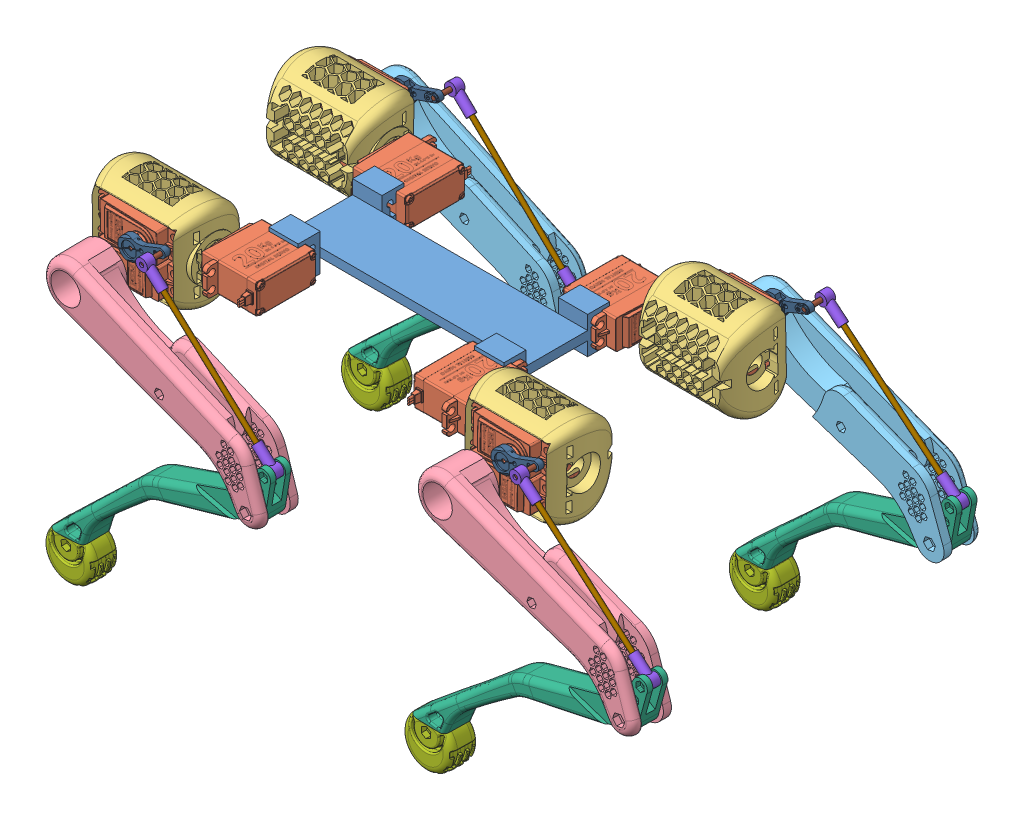
SolidWorks assembly ++Main_Assembly, configuration Default. Lengths in mm.
Overall size (432.52 222.98 243.72).
49 component instances, 11 part files, 112 mates.
Components (placement in the parent):
- Main_Body-1: Main_Body [Default] at (5.0922 136.3443 221.2659) size (160 25 72)
- DS3218MG_MS24_Digital_Servo_270-1: DS3218MG_MS24_Digital_Servo_270 [Default] at (145.0922 136.3151 160.5847) x (0 -1 0) z (0 0 1) size (20.1 45.99 55.6)
- DS3218MG_MS24_Digital_Servo_270-2: DS3218MG_MS24_Digital_Servo_270 [Default] at (145.0922 136.3151 281.9471) x (0 1 0) z (0 0 -1) size (20.1 45.99 55.6)
- DS3218MG_MS24_Digital_Servo_270-3: DS3218MG_MS24_Digital_Servo_270 [Default] at (-14.9078 136.3151 160.5847) x (0 1 0) z (0 0 1) size (20.1 45.99 55.6)
- DS3218MG_MS24_Digital_Servo_270-4: DS3218MG_MS24_Digital_Servo_270 [Default] at (-14.9078 136.3151 281.9471) x (0 -1 0) z (0 0 -1) size (20.1 45.99 55.6)
- HipJoint-1: HipJoint [Default] at (191.8422 136.3151 281.9471) x (1 0 0) z (0 0.020151 0.999797) size (67.23 58.77 49.18)
- HipJoint-2: HipJoint [Default] at (191.8422 136.3151 160.5847) x (1 0 0) z (0 0.018154 -0.999835) size (67.23 58.77 49.18)
- HipJoint-3: HipJoint [Default] at (-61.6578 136.3151 160.5847) x (-1 0 0) z (0 -0.032164 -0.999483) size (67.23 58.77 49.18)
- HipJoint-4: HipJoint [Default] at (-61.6578 136.3151 281.9471) x (-1 0 0) z (0 -0.01495 0.999888) size (67.23 58.77 49.18)
- DS3218MG_MS24_Digital_Servo_270-5: DS3218MG_MS24_Digital_Servo_270 [Default] at (-51.4078 147.1046 296.11) x (0 -0.999888 -0.01495) z (-1 0 0) size (20.1 45.99 55.6)
- DS3218MG_MS24_Digital_Servo_270-6: DS3218MG_MS24_Digital_Servo_270 [Default] at (-71.9078 125.107 295.7811) x (0 0.999888 0.01495) z (1 0 0) size (20.1 45.99 55.6)
- DS3218MG_MS24_Digital_Servo_270-7: DS3218MG_MS24_Digital_Servo_270 [Default] at (181.5922 125.5994 296.1659) x (0 0.999797 -0.020151) z (1 0 0) size (20.1 45.99 55.6)
- DS3218MG_MS24_Digital_Servo_270-8: DS3218MG_MS24_Digital_Servo_270 [Default] at (202.0922 147.6949 295.7206) x (0 -0.999797 0.020151) z (-1 0 0) size (20.1 45.99 55.6)
- DS3218MG_MS24_Digital_Servo_270-10: DS3218MG_MS24_Digital_Servo_270 [Default] at (201.5922 147.5674 146.7867) x (0 0.999835 0.018154) z (-1 0 0) size (20.1 45.99 55.6)
- DS3218MG_MS24_Digital_Servo_270-11: DS3218MG_MS24_Digital_Servo_270 [Default] at (182.0922 125.5711 146.3873) x (0 -0.999835 -0.018154) z (1 0 0) size (20.1 45.99 55.6)
- DS3218MG_MS24_Digital_Servo_270-12: DS3218MG_MS24_Digital_Servo_270 [Default] at (-71.4078 124.7705 146.949) x (0 -0.999483 0.032164) z (1 0 0) size (20.1 45.99 55.6)
- DS3218MG_MS24_Digital_Servo_270-13: DS3218MG_MS24_Digital_Servo_270 [Default] at (-51.9078 146.8591 146.2382) x (0 0.999483 -0.032164) z (-1 0 0) size (20.1 45.99 55.6)
- Left_Thigh-1: Left_Thigh [Default] at (238.4344 106.9954 326.3469) x (0 0.020151 0.999797) z (-0.94737 0.320075 -0.006451) size (26.29 49.21 165.28)
- Left_Thigh-2: Left_Thigh [Default] at (-16.0368 102.7909 325.2508) x (0 -0.01495 0.999888) z (-0.931184 0.36451 0.00545) size (26.29 49.21 165.28)
- Right_Thigh-1: Right_Thigh [Default] at (238.6676 105.2996 162.2219) x (0 -0.018154 0.999835) z (-0.942923 0.332955 0.006045) size (26.29 49.21 165.28)
- Right_Thigh-2: Right_Thigh [Default] at (-15.4072 103.7636 163.8334) x (0 0.032164 0.999483) z (-0.933343 0.358799 -0.011546) size (26.29 49.21 165.28)
- Leg_Universal-1: Leg_Universal [Default] at (-18.5337 16.056 324.454) x (0 -0.01495 0.999888) z (-0.987227 -0.159304 -0.002382) size (27.56 93.87 164.52)
- Leg_Universal-2: Leg_Universal [Default] at (-18.251 17.1977 120.0951) x (0 0.032164 0.999483) z (-0.989939 -0.14142 0.004551) size (27.56 93.87 164.52)
- Leg_Universal-3: Leg_Universal [Default] at (237.16 22.9219 114.2185) x (0 -0.018154 0.999835) z (-0.990021 -0.1409 -0.002558) size (27.56 93.87 164.52)
- Leg_Universal-4: Leg_Universal [Default] at (235.6218 28.8095 328.4229) x (0 0.020151 0.999797) z (-0.996606 -0.082305 0.001659) size (27.56 93.87 164.52)
- Feet-1: Feet [Default] at (-76.7895 -31.4649 323.4934) x (0 -0.01495 0.999888) z (-0.998583 -0.053205 -0.000796) size (21.73 29.66 33.85)
- Feet-2: Feet [Default] at (173.8572 -14.0583 329.0368) x (0 -0.020151 -0.999797) z (0.999703 -0.024346 0.000491) size (21.73 29.66 33.85)
- Feet-3: Feet [Default] at (178.5295 -23.4953 113.6258) x (0 -0.018154 0.999835) z (-0.999401 -0.034613 -0.000628) size (21.73 29.66 33.85)
- Feet-4: Feet [Default] at (-76.8547 -29.2243 121.8391) x (0 0.032164 0.999483) z (-0.99938 -0.035176 0.001132) size (21.73 29.66 33.85)
- Ball_Bearing_End_Joint-1: Ball_Bearing_End_Joint [Default] at (314.8505 81.1585 327.1177) x (0.639096 0.768971 -0.015498) z (0 -0.020151 -0.999797) size (8 20 6)
- Ball_Bearing_End_Joint-2: Ball_Bearing_End_Joint [Default] at (313.1644 79.8517 115.5023) x (0.650252 0.759593 0.013792) z (0 0.018154 -0.999835) size (8 20 6)
- Ball_Bearing_End_Joint-3: Ball_Bearing_End_Joint [Default] at (56.3978 74.4014 325.0763) x (0.685285 0.728193 0.010888) z (0 0.01495 -0.999888) size (8 20 6)
- Ball_Bearing_End_Joint-4: Ball_Bearing_End_Joint [Default] at (57.7206 74.1637 118.512) x (0.67212 0.74006 -0.023816) z (0 -0.032164 -0.999483) size (8 20 6)
- Long_Metal_Rod-1: Long_Metal_Rod [Default] at (13.4296 114.8287 325.6808) x (-0.138748 -0.132795 -0.981384) z (-0.728275 0.685209 0.010245) size (3 3 100)
- Long_Metal_Rod-2: Long_Metal_Rod [Default] at (14.0344 113.7983 117.2365) x (0.411304 0.478318 0.775913) z (-0.740443 0.671772 -0.021618) size (3 3 100)
- Long_Metal_Rod-3: Long_Metal_Rod [Default] at (269.472 118.8575 326.3579) x (0.046921 0.076552 0.995961) z (0.769127 -0.638967 0.012878) size (3 3 100)
- Long_Metal_Rod-4: Long_Metal_Rod [Default] at (268.341 118.2103 116.1987) x (-0.048668 -0.074954 0.995999) z (-0.759718 0.650145 0.011805) size (3 3 100)
- Servo_arm_25T-1: Servo_arm_25T [Default] at (-51.9078 146.219 126.3485) x (-0.94707 -0.320861 0.010325) z (-0.321027 0.94658 -0.030461) size (33.87 4.68 15)
- Servo_arm_25T-2: Servo_arm_25T [Default] at (201.5922 147.9287 126.89) x (-0.932997 -0.359824 -0.006533) z (-0.359884 0.932843 0.016938) size (33.87 4.68 15)
- Servo_arm_25T-3: Servo_arm_25T [Default] at (202.0922 148.0959 315.6166) x (-0.936228 -0.351321 0.007081) z (0.351392 -0.936038 0.018866) size (33.87 4.68 15)
- Servo_arm_25T-4: Servo_arm_25T [Default] at (-51.4078 146.807 316.0078) x (-0.930604 -0.365987 -0.005472) z (0.366028 -0.9305 -0.013913) size (33.87 4.68 15)
- Ball_Bearing_End_Joint-5: Ball_Bearing_End_Joint [Default] at (-29.5386 155.256 326.2852) x (0.685285 0.728193 0.010888) z (0 -0.01495 0.999888) size (8 20 6)
- Ball_Bearing_End_Joint-6: Ball_Bearing_End_Joint [Default] at (224.0935 156.5565 325.5981) x (-0.639096 -0.768971 0.015498) z (0 -0.020151 -0.999797) size (8 20 6)
- Ball_Bearing_End_Joint-7: Ball_Bearing_End_Joint [Default] at (223.5176 156.5688 116.8952) x (0.650252 0.759593 0.013792) z (0 -0.018154 0.999835) size (8 20 6)
- Ball_Bearing_End_Joint-8: Ball_Bearing_End_Joint [Default] at (-29.6517 153.4328 115.9611) x (-0.67212 -0.74006 0.023816) z (0 -0.032164 -0.999483) size (8 20 6)
- Short_Metal_Rod-1: Short_Metal_Rod [Default] at (-29.5386 155.3233 321.7857) x (0.999839 0.017951 0.000268) z (0 -0.01495 0.999888) size (3 3 16.55)
- Short_Metal_Rod-2: Short_Metal_Rod [Default] at (224.0935 156.4658 321.099) x (1 0 0) z (0 0.020151 0.999797) size (3 3 16.55)
- Short_Metal_Rod-3: Short_Metal_Rod [Default] at (223.5176 156.4191 125.1439) x (1 0.000002 0) z (0 -0.018154 0.999835) size (3 3 16.55)
- Short_Metal_Rod-4: Short_Metal_Rod [Default] at (-29.6517 153.6981 124.2068) x (0.999998 -0.001781 0.000057) z (0 0.032164 0.999483) size (3 3 16.55)
Mates (geometry in assembly coordinates):
- Coincident1: coincident anti-aligned: plane of Body-1 through (145.0922 136.3443 251.9471) normal (0 0 1); plane of DS3218MG MS24 Digital Servo 270-2 through (125.0922 126.3151 251.9471) normal (0 0 -1)
- Coincident2: coincident anti-aligned: plane of Body-1 through (145.0922 126.3151 221.2659) normal (0 1 0); plane of DS3218MG MS24 Digital Servo 270-2 through (156.0922 126.3151 290.9471) normal (0 -1 0)
- Coincident3: coincident anti-aligned: plane of Body-1 through (145.0922 136.3443 221.2659) normal (1 0 0); plane of DS3218MG MS24 Digital Servo 270-2 through (145.0922 145.3151 254.9471) normal (-1 0 0)
- Coincident4: coincident anti-aligned: plane of Body-1 through (145.0922 126.3151 221.2659) normal (0 1 0); plane of DS3218MG MS24 Digital Servo 270-1 through (156.0922 126.3151 189.5847) normal (0 -1 0)
- Coincident5: coincident anti-aligned: plane of Body-1 through (145.0922 136.3443 221.2659) normal (1 0 0); plane of DS3218MG MS24 Digital Servo 270-1 through (145.0922 127.3151 187.5847) normal (-1 0 0)
- Coincident6: coincident anti-aligned: plane of Body-1 through (145.0922 136.3443 190.5847) normal (0 0 -1); plane of DS3218MG MS24 Digital Servo 270-1 through (125.0922 146.3151 190.5847) normal (0 0 1)
- Coincident7: coincident anti-aligned: plane of Body-1 through (-14.9078 126.3151 221.2659) normal (0 1 0); plane of DS3218MG MS24 Digital Servo 270-3 through (-25.9078 126.3151 151.5847) normal (0 -1 0)
- Coincident8: coincident anti-aligned: plane of Body-1 through (-14.9078 136.3443 190.5847) normal (0 0 -1); plane of DS3218MG MS24 Digital Servo 270-3 through (5.0922 126.3151 190.5847) normal (0 0 1)
- Coincident9: coincident anti-aligned: plane of Body-1 through (-14.9078 136.3443 221.2659) normal (-1 0 0); plane of DS3218MG MS24 Digital Servo 270-3 through (-14.9078 145.3151 187.5847) normal (1 0 0)
- Coincident15: coincident anti-aligned: plane of Body-1 through (-14.9078 136.3443 251.9471) normal (0 0 1); plane of DS3218MG MS24 Digital Servo 270-4 through (5.0922 146.3151 251.9471) normal (0 0 -1)
- Coincident16: coincident anti-aligned: plane of Body-1 through (-14.9078 126.3151 221.2659) normal (0 1 0); plane of DS3218MG MS24 Digital Servo 270-4 through (5.0922 126.3151 291.9471) normal (0 -1 0)
- Coincident17: coincident anti-aligned: plane of Body-1 through (-14.9078 136.3443 221.2659) normal (-1 0 0); plane of DS3218MG MS24 Digital Servo 270-4 through (-14.9078 127.3151 254.9471) normal (1 0 0)
- Concentric1: concentric aligned: circle of DS3218MG MS24 Digital Servo 270-2; circle of HipJoint-1
- Distance2: distance = 0 mm anti-aligned: plane of DS3218MG MS24 Digital Servo 270-2 through (163.4922 136.3151 281.9471) normal (1 0 0); plane of HipJoint-1 through (163.4922 136.3151 281.9471) normal (-1 0 0)
- Concentric2: concentric aligned: circle of DS3218MG MS24 Digital Servo 270-1; circle of HipJoint-2
- Distance1: distance = 0 mm anti-aligned: plane of HipJoint-2 through (163.4922 136.3151 160.5847) normal (-1 0 0); plane of DS3218MG MS24 Digital Servo 270-1 through (163.4922 136.3151 160.5847) normal (1 0 0)
- Concentric3: concentric aligned: circle of DS3218MG MS24 Digital Servo 270-3; circle of HipJoint-3
- Distance3: distance = 0 mm anti-aligned: plane of HipJoint-3 through (-33.3078 136.3151 160.5847) normal (1 0 0); plane of DS3218MG MS24 Digital Servo 270-3 through (-33.3078 136.3151 160.5847) normal (-1 0 0)
- Concentric4: concentric aligned: circle of DS3218MG MS24 Digital Servo 270-4; circle of HipJoint-4
- Distance4: distance = 0 mm anti-aligned: plane of HipJoint-4 through (-33.3078 136.3151 281.9471) normal (1 0 0); plane of DS3218MG MS24 Digital Servo 270-4 through (-33.3078 136.3151 281.9471) normal (-1 0 0)
- Coincident23: coincident anti-aligned: plane of HipJoint-4 through (-81.9078 136.5244 267.9487) normal (1 0 0); plane of DS3218MG MS24 Digital Servo 270-6 through (-81.9078 115.4071 275.6338) normal (-1 0 0)
- Coincident24: coincident anti-aligned: plane of HipJoint-4 through (-61.6578 136.1058 295.9456) normal (0 -0.01495 0.999888); plane of DS3218MG MS24 Digital Servo 270-6 through (-44.9078 134.106 295.9157) normal (0 0.01495 -0.999888)
- Coincident25: coincident anti-aligned: plane of HipJoint-4 through (-61.6578 135.5245 267.9337) normal (0 -0.999888 -0.01495); plane of DS3218MG MS24 Digital Servo 270-6 through (-81.9078 135.4049 275.9328) normal (0 0.999888 0.01495)
- Coincident26: coincident anti-aligned: plane of HipJoint-4 through (-41.4078 136.5244 267.9487) normal (-1 0 0); plane of DS3218MG MS24 Digital Servo 270-5 through (-41.4078 157.4024 276.2617) normal (1 0 0)
- Coincident27: coincident anti-aligned: plane of HipJoint-4 through (-61.6578 136.1058 295.9456) normal (0 -0.01495 0.999888); plane of DS3218MG MS24 Digital Servo 270-5 through (-78.4078 138.1056 295.9755) normal (0 0.01495 -0.999888)
- Coincident28: coincident anti-aligned: plane of HipJoint-4 through (-61.6578 137.5243 267.9636) normal (0 0.999888 0.01495); plane of DS3218MG MS24 Digital Servo 270-5 through (-41.4078 137.4047 275.9627) normal (0 -0.999888 -0.01495)
- Coincident29: coincident anti-aligned: plane of HipJoint-1 through (212.0922 136.033 267.95) normal (-1 0 0); plane of DS3218MG MS24 Digital Servo 270-8 through (212.0922 157.2899 275.5232) normal (1 0 0)
- Coincident30: coincident anti-aligned: plane of HipJoint-1 through (191.8422 157.1287 267.5248) normal (0 -0.999797 0.020151); plane of DS3218MG MS24 Digital Servo 270-8 through (212.0922 157.2899 275.5232) normal (0 0.999797 -0.020151)
- Coincident31: coincident anti-aligned: plane of HipJoint-1 through (191.8422 136.5972 295.9443) normal (0 0.020151 0.999797); plane of DS3218MG MS24 Digital Servo 270-8 through (175.0922 138.6968 295.902) normal (0 -0.020151 -0.999797)
- Coincident32: coincident anti-aligned: plane of HipJoint-1 through (171.5922 136.033 267.95) normal (1 0 0); plane of DS3218MG MS24 Digital Servo 270-7 through (171.5922 115.1984 276.3715) normal (-1 0 0)
- Coincident33: coincident anti-aligned: plane of HipJoint-1 through (191.8422 135.0332 267.9701) normal (0 -0.999797 0.020151); plane of DS3218MG MS24 Digital Servo 270-7 through (171.5922 135.1944 275.9685) normal (0 0.999797 -0.020151)
- Coincident34: coincident anti-aligned: plane of HipJoint-1 through (191.8422 136.5972 295.9443) normal (0 0.020151 0.999797); plane of DS3218MG MS24 Digital Servo 270-7 through (208.5922 134.5976 295.9846) normal (0 -0.020151 -0.999797)
- Concentric6: concentric aligned: circle of DS3218MG MS24 Digital Servo 270-6; circle of Left Thigh-2
- Distance18: distance = 2 mm anti-aligned: plane of Left_Thigh-2 through (-71.9078 124.802 316.1788) normal (0 0.01495 -0.999888); plane of DS3218MG_MS24_Digital_Servo_270-6 through (-71.9078 124.8319 314.1791) normal (0 -0.01495 0.999888)
- Concentric7: concentric aligned: circle of DS3218MG MS24 Digital Servo 270-7; circle of Left Thigh-1
- Distance19: distance = 2 mm anti-aligned: plane of Left_Thigh-1 through (181.5922 126.0105 316.5618) normal (0 -0.020151 -0.999797); plane of DS3218MG_MS24_Digital_Servo_270-7 through (181.5922 125.9702 314.5622) normal (0 0.020151 0.999797)
- Coincident37: coincident anti-aligned: plane of HipJoint-2 through (212.0922 136.0609 174.5824) normal (-1 0 0); plane of DS3218MG MS24 Digital Servo 270-9 through (212.0922 135.2063 166.5656) normal (1 0 0)
- Coincident38: coincident anti-aligned: plane of HipJoint-2 through (191.8422 135.0611 174.5643) normal (0 -0.999835 -0.018154); plane of DS3218MG MS24 Digital Servo 270-9 through (172.0922 135.2063 166.5656) normal (0 0.999835 0.018154)
- Coincident39: coincident anti-aligned: plane of HipJoint-2 through (191.8422 136.5692 146.587) normal (0 0.018154 -0.999835); plane of DS3218MG MS24 Digital Servo 270-9 through (209.0922 116.5725 146.224) normal (0 -0.018154 0.999835)
- Coincident40: coincident anti-aligned: plane of HipJoint-2 through (171.5922 136.0609 174.5824) normal (1 0 0); plane of DS3218MG MS24 Digital Servo 270-10 through (171.5922 137.206 166.6019) normal (-1 0 0)
- Coincident41: coincident anti-aligned: plane of HipJoint-2 through (191.8422 137.0608 174.6006) normal (0 0.999835 0.018154); plane of DS3218MG MS24 Digital Servo 270-10 through (211.5922 137.206 166.6019) normal (0 -0.999835 -0.018154)
- Coincident42: coincident anti-aligned: plane of HipJoint-2 through (191.8422 136.5692 146.587) normal (0 0.018154 -0.999835); plane of DS3218MG MS24 Digital Servo 270-10 through (174.5922 156.5659 146.9501) normal (0 -0.018154 0.999835)
- Coincident43: coincident anti-aligned: plane of HipJoint-3 through (-41.4078 136.7654 174.5775) normal (-1 0 0); plane of DS3218MG MS24 Digital Servo 270-11 through (-41.4078 135.4086 166.617) normal (1 0 0)
- Coincident44: coincident anti-aligned: plane of HipJoint-3 through (-61.6578 135.8648 146.592) normal (0 -0.032164 -0.999483); plane of DS3218MG MS24 Digital Servo 270-11 through (-44.4078 115.7752 147.2385) normal (0 0.032164 0.999483)
- Coincident45: coincident anti-aligned: plane of HipJoint-3 through (-61.6578 115.6763 175.2561) normal (0 0.999483 -0.032164); plane of DS3218MG MS24 Digital Servo 270-11 through (-81.4078 115.419 167.2603) normal (0 -0.999483 0.032164)
- Coincident46: coincident anti-aligned: plane of HipJoint-3 through (-81.9078 136.7654 174.5775) normal (1 0 0); plane of DS3218MG MS24 Digital Servo 270-12 through (-81.9078 137.5075 166.5495) normal (-1 0 0)
- Coincident47: coincident anti-aligned: plane of HipJoint-3 through (-61.6578 137.7649 174.5453) normal (0 0.999483 -0.032164); plane of DS3218MG MS24 Digital Servo 270-12 through (-41.9078 137.5075 166.5495) normal (0 -0.999483 0.032164)
- Coincident48: coincident anti-aligned: plane of HipJoint-3 through (-61.6578 135.8648 146.592) normal (0 -0.032164 -0.999483); plane of DS3218MG MS24 Digital Servo 270-12 through (-78.9078 155.8544 145.9487) normal (0 0.032164 0.999483)
- Concentric8: concentric aligned: circle of DS3218MG MS24 Digital Servo 270-9; circle of Right Thigh-1
- Distance20: distance = 2 mm anti-aligned: plane of DS3218MG MS24 Digital Servo 270-9 through (182.0922 125.9051 127.9904) normal (0 0.018154 -0.999835); plane of Right Thigh-1 through (182.0922 125.9414 125.9907) normal (0 -0.018154 0.999835)
- Concentric9: concentric anti-aligned: circle of DS3218MG MS24 Digital Servo 270-11; circle of Right Thigh-2
- Distance21: distance = 2 mm anti-aligned: plane of DS3218MG MS24 Digital Servo 270-11 through (-71.4078 124.1787 128.5585) normal (0 -0.032164 -0.999483); plane of Right Thigh-2 through (-71.4078 124.1144 126.5596) normal (0 0.032164 0.999483)
- Concentric10: concentric aligned: circle of Left_Thigh-2; cylinder of Leg_Universal-1 through (49.413 52.1078 350.3136) axis (0 0.01495 -0.999888) radius 5.025
- Distance10: distance = 0 mm anti-aligned: plane of Leg_Universal-1 through (-18.5337 15.9513 331.4532) normal (0 -0.01495 0.999888); plane of Left_Thigh-2 through (-16.0368 102.6788 332.7499) normal (0 0.01495 -0.999888)
- Concentric11: concentric aligned: circle of Left_Thigh-1; cylinder of Leg_Universal-4 through (306.1881 60.3716 353.1096) axis (0 -0.020151 -0.999797) radius 5.025
- Distance11: distance = 0 mm anti-aligned: plane of Left_Thigh-1 through (238.4344 107.1466 333.8454) normal (0 -0.020151 -0.999797); plane of Leg_Universal-4 through (235.6218 28.9505 335.4214) normal (0 0.020151 0.999797)
- Concentric12: concentric aligned: circle of Right_Thigh-1; cylinder of Leg_Universal-3 through (305.7729 57.6202 140.1705) axis (0 0.018154 -0.999835) radius 5.025
- Distance12: distance = 0 mm anti-aligned: plane of Leg_Universal-3 through (237.16 23.049 107.2197) normal (0 0.018154 -0.999835); plane of Right Thigh-1 through (238.6676 106.2709 108.7308) normal (0 -0.018154 0.999835)
- Concentric13: concentric aligned: circle of Right_Thigh-2; cylinder of Leg_Universal-2 through (50.3417 53.197 144.2674) axis (0 -0.032164 -0.999483) radius 5.025
- Distance13: distance = 0 mm anti-aligned: plane of Leg_Universal-2 through (-18.251 16.9726 113.0987) normal (0 -0.032164 -0.999483); plane of Right Thigh-2 through (-15.4072 102.0429 110.3611) normal (0 0.032164 0.999483)
- Coincident55: coincident anti-aligned: plane of Leg_Universal-1 through (-72.9089 13.2186 320.4111) normal (0.998583 0.053205 0.000796); plane of Feet-1 through (-70.2275 -37.1526 323.4084) normal (-0.998583 -0.053205 -0.000796)
- Coincident56: coincident anti-aligned: plane of Leg_Universal-1 through (-18.5337 15.9962 328.4535) normal (0 -0.01495 0.999888); plane of Feet-1 through (-76.4686 -37.5487 327.653) normal (0 0.01495 -0.999888)
- Coincident57: coincident anti-aligned: plane of Leg_Universal-1 through (-16.4376 -23.1266 313.867) normal (0.053211 -0.998472 -0.014929); plane of Feet-1 through (-77.054 -26.3255 311.7632) normal (-0.053211 0.998472 0.014929)
- Coincident58: coincident anti-aligned: plane of Leg_Universal-4 through (235.6218 28.8901 332.4221) normal (0 0.020151 0.999797); plane of Feet-2 through (173.7104 -19.9991 333.4074) normal (0 -0.020151 -0.999797)
- Coincident59: coincident anti-aligned: plane of Leg_Universal-4 through (181.1856 30.0546 324.397) normal (0.999703 -0.024346 0.000491); plane of Feet-2 through (179.9585 -20.2369 329.1613) normal (-0.999703 0.024346 -0.000491)
- Coincident60: coincident anti-aligned: plane of Leg_Universal-4 through (234.6625 -10.7646 319.2184) normal (-0.024351 -0.9995 0.020145); plane of Feet-2 through (173.9782 -8.8524 340.7401) normal (0.024351 0.9995 -0.020145)
- Coincident61: coincident anti-aligned: plane of Leg_Universal-3 through (237.16 22.9945 110.2192) normal (0 0.018154 -0.999835); plane of Feet-3 through (178.7383 -29.443 109.2671) normal (0 -0.018154 0.999835)
- Coincident62: coincident anti-aligned: plane of Leg_Universal-3 through (170.7475 20.6944 110.1774) normal (-0.999401 -0.034613 -0.000628); plane of Feet-3 through (172.492 -29.7364 113.5125) normal (0.999401 0.034613 0.000628)
- Coincident63: coincident anti-aligned: plane of Leg_Universal-3 through (238.5237 -16.2587 103.5055) normal (0.034619 -0.999236 -0.018143); plane of Feet-3 through (178.3575 -18.3142 101.9121) normal (-0.034619 0.999236 0.018143)
- Coincident64: coincident anti-aligned: plane of Feet-4 through (-82.8886 -35.4667 122.04) normal (0.99938 0.035176 -0.001132); plane of Leg_Universal-2 through (-84.6622 14.7315 116.1724) normal (-0.99938 -0.035176 0.001132)
- Coincident66: coincident anti-aligned: plane of Leg_Universal-2 through (-16.8646 -22.4714 111.3665) normal (0.035194 -0.998863 0.032144); plane of Feet-4 through (-77.0297 -24.6391 109.8796) normal (-0.035194 0.998863 -0.032144)
- Coincident67: coincident anti-aligned: plane of Leg_Universal-2 through (-18.251 17.0691 116.0971) normal (0 -0.032164 -0.999483); plane of Feet-4 through (-76.6425 -35.3836 117.7851) normal (0 0.032164 0.999483)
- Coincident68: coincident aligned: circle of Leg_Universal-4; circle of ball bearing end joint-1
- Coincident69: coincident anti-aligned: circle of Leg_Universal-3; circle of ball bearing end joint-2
- Coincident70: coincident anti-aligned: circle of Leg_Universal-2; circle of ball bearing end joint-4
- Coincident71: coincident aligned: circle of Leg_Universal-1; circle of ball bearing end joint-3
- Concentric14: concentric aligned: cylinder of ball bearing end joint-2 through (306.3269 85.703 115.6085) axis (-0.759718 0.650145 0.011805) radius 1.5; cylinder of long-4 through (306.3269 85.703 115.6085) axis (-0.759718 0.650145 0.011805) radius 1.5
- Concentric15: concentric anti-aligned: cylinder of ball bearing end joint-1 through (307.9284 86.9092 327.0018) axis (-0.769127 0.638967 -0.012878) radius 1.5; cylinder of long-3 through (231.0157 150.8058 325.714) axis (0.769127 -0.638967 0.012878) radius 1.5
- Concentric16: concentric aligned: cylinder of ball bearing end joint-3 through (49.8433 80.5683 325.1685) axis (-0.728275 0.685209 0.010245) radius 1.5; cylinder of long-1 through (49.8433 80.5683 325.1685) axis (-0.728275 0.685209 0.010245) radius 1.5
- Concentric17: concentric aligned: cylinder of ball bearing end joint-4 through (51.0566 80.2097 118.3174) axis (-0.740443 0.671772 -0.021618) radius 1.5; cylinder of long-2 through (51.0566 80.2097 118.3174) axis (-0.740443 0.671772 -0.021618) radius 1.5
- Concentric25: concentric anti-aligned: cylinder of long-1 through (49.8433 80.5683 325.1685) axis (-0.728275 0.685209 0.010245) radius 1.5; cylinder of ball bearing end joint-5 through (-22.9842 149.0891 326.193) axis (0.728275 -0.685209 -0.010245) radius 1.5
- Concentric23: concentric anti-aligned: cylinder of long-4 through (306.3269 85.703 115.6085) axis (-0.759718 0.650145 0.011805) radius 1.5; cylinder of ball bearing end joint-7 through (230.3551 150.7175 116.789) axis (0.759718 -0.650145 -0.011805) radius 1.5
- Concentric22: concentric anti-aligned: cylinder of long-2 through (51.0566 80.2097 118.3174) axis (-0.740443 0.671772 -0.021618) radius 1.5; cylinder of ball bearing end joint-8 through (-22.9877 147.3868 116.1556) axis (0.740443 -0.671772 0.021618) radius 1.5
- Concentric24: concentric aligned: cylinder of long-3 through (231.0157 150.8058 325.714) axis (0.769127 -0.638967 0.012878) radius 1.5; cylinder of ball bearing end joint-6 through (231.0157 150.8058 325.714) axis (0.769127 -0.638967 0.012878) radius 1.5
- Distance14: distance = 0 mm anti-aligned: plane of ball bearing end joint-4 through (51.0566 80.2097 118.3174) normal (-0.740443 0.671772 -0.021618); plane of long-2 through (51.0566 80.2097 118.3174) normal (0.740443 -0.671772 0.021618)
- Distance15: distance = 0 mm anti-aligned: plane of ball bearing end joint-2 through (306.3269 85.703 115.6085) normal (-0.759718 0.650145 0.011805); plane of long-4 through (306.3269 85.703 115.6085) normal (0.759718 -0.650145 -0.011805)
- Distance16: distance = 0 mm anti-aligned: plane of Ball_Bearing_End_Joint-1 through (307.9284 86.9092 327.0018) normal (-0.769127 0.638967 -0.012878); plane of Long_Metal_Rod-3 through (307.9284 86.9092 327.0018) normal (0.769127 -0.638967 0.012878)
- Distance17: distance = 0 mm anti-aligned: plane of Ball_Bearing_End_Joint-3 through (49.8433 80.5683 325.1685) normal (-0.728275 0.685209 0.010245); plane of Long_Metal_Rod-1 through (49.8433 80.5683 325.1685) normal (0.728275 -0.685209 -0.010245)
- Concentric18: concentric anti-aligned: circle of DS3218MG MS24 Digital Servo 270-10; circle of Servo_arm_25T-2
- Distance22: distance = 0 mm anti-aligned: plane of DS3218MG MS24 Digital Servo 270-10 through (201.5922 147.9015 128.3898) normal (0 0.018154 -0.999835); plane of Servo_arm_25T-2 through (201.5922 147.9015 128.3898) normal (0 -0.018154 0.999835)
- Concentric19: concentric anti-aligned: circle of DS3218MG MS24 Digital Servo 270-12; circle of Servo_arm_25T-1
- Distance23: distance = 0 mm anti-aligned: plane of DS3218MG MS24 Digital Servo 270-12 through (-51.9078 146.2673 127.8477) normal (0 -0.032164 -0.999483); plane of Servo_arm_25T-1 through (-51.9078 146.2673 127.8477) normal (0 0.032164 0.999483)
- Concentric20: concentric anti-aligned: circle of DS3218MG MS24 Digital Servo 270-5; circle of Servo_arm_25T-4
- Distance24: distance = 0 mm anti-aligned: plane of DS3218MG_MS24_Digital_Servo_270-5 through (-51.4078 146.8295 314.508) normal (0 -0.01495 0.999888); plane of Servo_arm_25T-4 through (-51.4078 146.8295 314.508) normal (0 0.01495 -0.999888)
- Concentric21: concentric aligned: circle of DS3218MG MS24 Digital Servo 270-8; circle of Servo_arm_25T-3
- Distance25: distance = 0 mm anti-aligned: plane of DS3218MG_MS24_Digital_Servo_270-8 through (202.0922 148.0657 314.1169) normal (0 0.020151 0.999797); plane of Servo_arm_25T-3 through (202.0922 148.0657 314.1169) normal (0 -0.020151 -0.999797)
- Distance26: distance = 0 mm anti-aligned: plane of long-2 through (-22.9877 147.3868 116.1556) normal (-0.740443 0.671772 -0.021618); plane of ball bearing end joint-8 through (-22.9877 147.3868 116.1556) normal (0.740443 -0.671772 0.021618)
- Distance28: distance = 0 mm anti-aligned: plane of ball bearing end joint-7 through (230.3551 150.7175 116.789) normal (0.759718 -0.650145 -0.011805); plane of long-4 through (230.3551 150.7175 116.789) normal (-0.759718 0.650145 0.011805)
- Distance29: distance = 0 mm anti-aligned: plane of Ball_Bearing_End_Joint-6 through (231.0157 150.8058 325.714) normal (0.769127 -0.638967 0.012878); plane of Long_Metal_Rod-3 through (231.0157 150.8058 325.714) normal (-0.769127 0.638967 -0.012878)
- Distance30: distance = 0 mm anti-aligned: plane of Ball_Bearing_End_Joint-5 through (-22.9842 149.0891 326.193) normal (0.728275 -0.685209 -0.010245); plane of Long_Metal_Rod-1 through (-22.9842 149.0891 326.193) normal (-0.728275 0.685209 0.010245)
- Concentric28: concentric aligned: circle of Servo_arm_25T-3; circle of short-2
- Concentric29: concentric anti-aligned: circle of Servo_arm_25T-2; circle of short-3
- Distance31: distance = 0 mm aligned: plane of short-3 through (223.5176 156.3029 131.5428) normal (0 -0.018154 0.999835); plane of Servo_arm_25T-2 through (220.7851 158.0621 131.5748) normal (0 -0.018154 0.999835)
- Concentric30: concentric anti-aligned: circle of Servo_arm_25T-1; circle of short-4
- Distance32: distance = 0 mm aligned: plane of short-4 through (-29.6517 153.904 130.6035) normal (0 0.032164 0.999483); plane of Servo_arm_25T-1 through (-32.3092 155.7739 130.5433) normal (0 0.032164 0.999483)
- Concentric31: concentric aligned: circle of Servo_arm_25T-4; circle of short-1
- Distance34: distance = 0 mm aligned: plane of Servo_arm_25T-4 through (-30.361 152.3311 311.5899) normal (0 0.01495 -0.999888); plane of Short_Metal_Rod-1 through (-29.5386 155.475 311.6369) normal (0 0.01495 -0.999888)
- Concentric32: concentric anti-aligned: cylinder of ball bearing end joint-8 through (-29.6517 153.5293 118.9595) axis (0 -0.032164 -0.999483) radius 1.5; cylinder of short-4 through (-29.6517 153.3717 114.0621) axis (0 0.032164 0.999483) radius 1.5
- Concentric33: concentric aligned: cylinder of ball bearing end joint-7 through (223.5176 156.6233 113.8957) axis (0 -0.018154 0.999835) radius 1.5; cylinder of short-3 through (223.5176 156.6033 114.9955) axis (0 -0.018154 0.999835) radius 1.5
- Concentric34: concentric anti-aligned: cylinder of ball bearing end joint-6 through (224.0935 156.617 328.5975) axis (0 -0.020151 -0.999797) radius 1.5; cylinder of short-2 through (224.0935 156.2613 310.9511) axis (0 0.020151 0.999797) radius 1.5
- Distance35: distance = 0 mm aligned: plane of Short_Metal_Rod-2 through (224.0935 156.2613 310.9511) normal (0 -0.020151 -0.999797); plane of Servo_arm_25T-3 through (223.2219 153.131 311.0142) normal (0 -0.020151 -0.999797)
- Concentric35: concentric aligned: cylinder of ball bearing end joint-5 through (-29.5386 155.3008 323.2856) axis (0 -0.01495 0.999888) radius 1.5; cylinder of short-1 through (-29.5386 155.475 311.6369) axis (0 -0.01495 0.999888) radius 1.5
